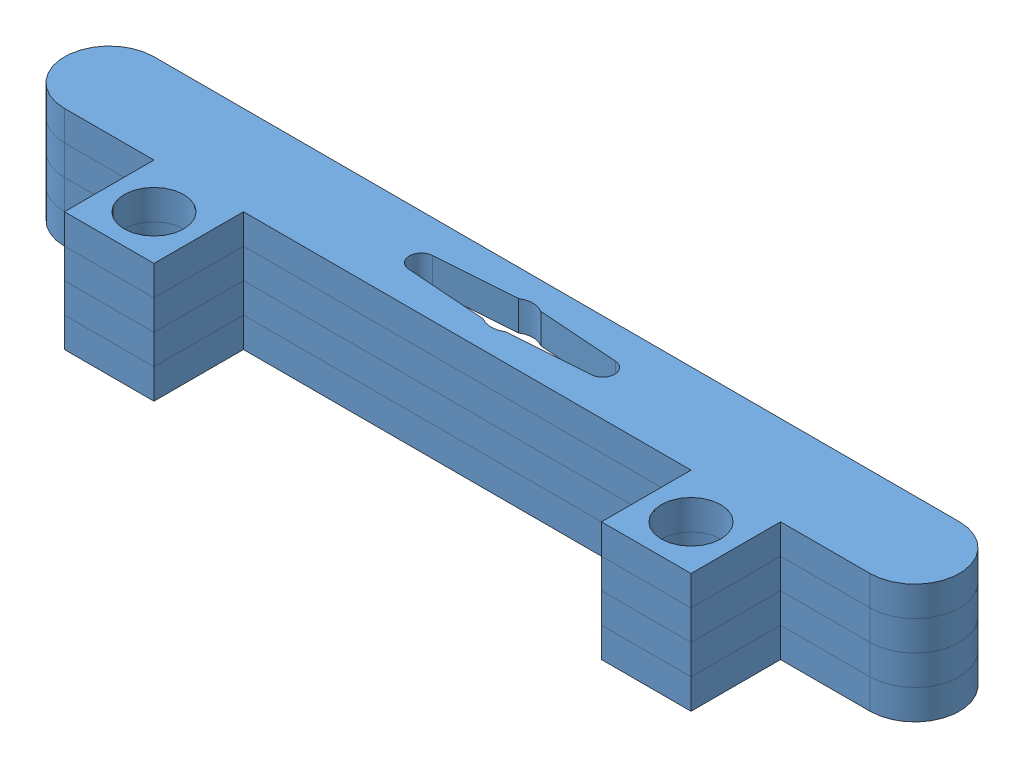
SolidWorks assembly Balance Assembly, configuration Default. Lengths in mm.
Overall size (150 20 15).
4 component instances, 1 part files, 9 mates.
Components (placement in the parent):
- Balance-1: Balance [Trough] at (74.8041 81.8567 102.7792) size (150 5 15)
- Balance-2: Balance [Trough] at (74.8041 86.8567 102.7792) size (150 5 15)
- Balance-4: Balance [Servo] at (74.8041 91.8567 102.7792) size (150 5 15)
- Balance-7: Balance [Default] at (74.8041 76.8567 102.7792) size (150 5 15)
Mates (geometry in assembly coordinates):
- Concentric1: concentric: cylinder of Balance-2 through (119.8041 91.8567 117.7792) axis (0 -1 0) radius 5; cylinder of Balance-4 through (119.8041 96.8567 117.7792) axis (0 -1 0) radius 5
- Concentric2: concentric: cylinder of Balance-1 through (119.8041 86.8567 117.7792) axis (0 -1 0) radius 5; cylinder of Balance-4 through (119.8041 96.8567 117.7792) axis (0 -1 0) radius 5
- Concentric5: concentric: cylinder of Balance-1 through (29.8041 86.8567 117.7792) axis (0 -1 0) radius 5; cylinder of Balance-2 through (29.8041 91.8567 117.7792) axis (0 -1 0) radius 5
- Concentric6: concentric: cylinder of Balance-1 through (29.8041 86.8567 117.7792) axis (0 -1 0) radius 5; cylinder of Balance-4 through (29.8041 96.8567 117.7792) axis (0 -1 0) radius 5
- Coincident3: coincident: plane of Balance-1 through (74.8041 86.8567 102.7792) normal (0 1 0); plane of Balance-2 through (74.8041 86.8567 102.7792) normal (0 -1 0)
- Coincident4: coincident: plane of Balance-2 through (74.8041 91.8567 102.7792) normal (0 1 0); plane of Balance-4 through (74.8041 91.8567 102.7792) normal (0 -1 0)
- Concentric7: concentric: cylinder of Balance-1 through (29.8041 86.8567 117.7792) axis (0 -1 0) radius 5; cylinder of Balance-7 through (29.8041 81.8567 117.7792) axis (0 -1 0) radius 5
- Concentric8: concentric: cylinder of Balance-1 through (119.8041 86.8567 117.7792) axis (0 -1 0) radius 5; cylinder of Balance-7 through (119.8041 81.8567 117.7792) axis (0 -1 0) radius 5
- Coincident5: coincident anti-aligned: plane of Balance-1 through (74.8041 81.8567 102.7792) normal (0 -1 0); plane of Balance-7 through (74.8041 81.8567 102.7792) normal (0 1 0)
